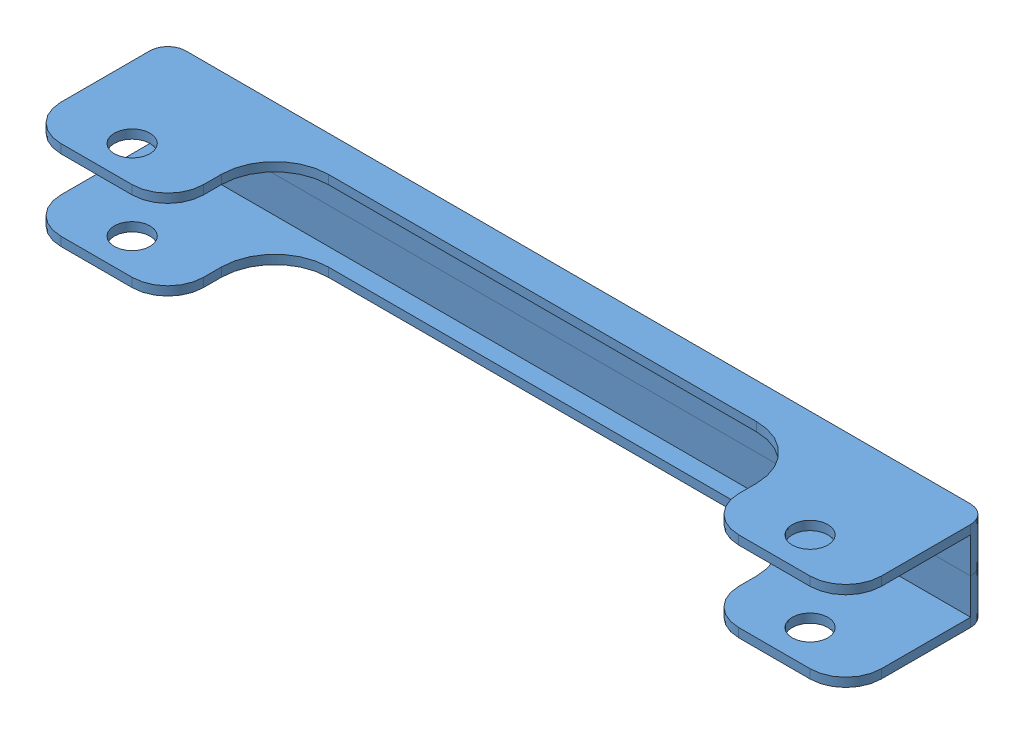
SolidWorks assembly Small wheels bracket, configuration Default. Lengths in mm.
Overall size (230 25 40).
2 component instances, 1 part files, 3 mates.
Components (placement in the parent):
- small horizontal wheeler-1: small horizontal wheeler [Default] at (8.5861 111.805 222.9029) size (230 12.5 40)
- small horizontal wheeler-2: small horizontal wheeler [Default] at (82.4884 86.805 222.9029) x (-1 0 0) z (0 0 1) size (230 12.5 40)
Mates (geometry in assembly coordinates):
- Coincident1: coincident anti-aligned: plane of small horizontal wheeler-1 through (8.5861 99.305 114.6299) normal (0 -1 0); plane of small horizontal wheeler-2 through (82.4884 99.305 114.6299) normal (0 1 0)
- Coincident2: coincident aligned: plane of small horizontal wheeler-1 through (-69.4628 61.805 118.7343) normal (-1 0 0); plane of small horizontal wheeler-2 through (-69.4628 136.805 114.0722) normal (-1 0 0)
- Coincident3: coincident aligned: plane of small horizontal wheeler-1 through (8.5861 71.805 119.6299) normal (0 0 -1); plane of small horizontal wheeler-2 through (82.4884 126.805 119.6299) normal (0 0 -1)
